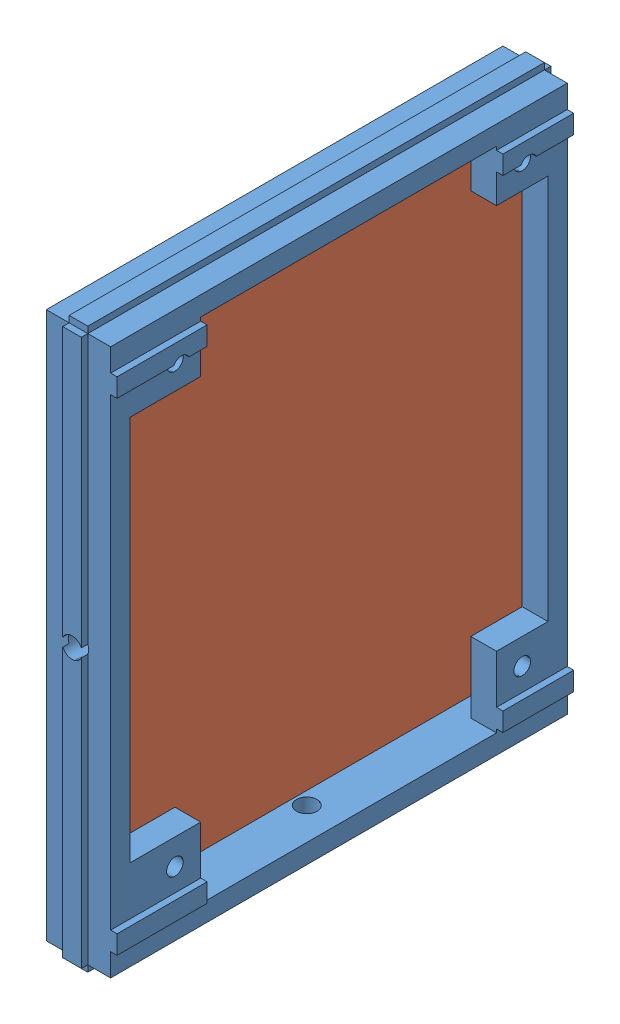
SolidWorks assembly Assem5, configuration Default. Lengths in mm.
Overall size (15.6 87 73).
11 component instances, 3 part files, 3 mates.
Components (placement in the parent):
- RLY08MakerBeamSupport-1: RLY08MakerBeamSupport [Default] at (8.7993 1.6144 41.7452) size (11 87 73)
- RLY08BoardAssembly-1: RLY08BoardAssembly [Default] at (44.7396 -28.8553 63.151) x (0 -1 0) z (-1 0 0) size (76 62 10.6)
  - RLY08Board-1: RLY08Board [Default] at (-74.4697 12.5942 29.9403) size (76 62 1.6)
  - Relay-ED2-5NU-1: Relay-ED2-5NU [Default] at (-96.9697 -8.9058 31.5403) size (14.8 7.35 9)
  - Relay-ED2-5NU-2: Relay-ED2-5NU [Default] at (-96.9697 2.5942 31.5403) size (14.8 7.35 9)
  - Relay-ED2-5NU-3: Relay-ED2-5NU [Default] at (-96.9697 14.0942 31.5403) size (14.8 7.35 9)
  - Relay-ED2-5NU-4: Relay-ED2-5NU [Default] at (-96.9697 25.5942 31.5403) size (14.8 7.35 9)
  - Relay-ED2-5NU-5: Relay-ED2-5NU [Default] at (-66.3697 -8.9058 31.5403) size (14.8 7.35 9)
  - Relay-ED2-5NU-6: Relay-ED2-5NU [Default] at (-66.3697 2.5942 31.5403) size (14.8 7.35 9)
  - Relay-ED2-5NU-7: Relay-ED2-5NU [Default] at (-66.3697 14.0942 31.5403) size (14.8 7.35 9)
  - Relay-ED2-5NU-8: Relay-ED2-5NU [Default] at (-66.3697 25.5942 31.5403) size (14.8 7.35 9)
Mates (geometry in assembly coordinates):
- Concentric1: concentric: cylinder of RLY08MakerBeamSupport-1 through (19.7993 79.6144 48.7452) axis (-1 0 0) radius 1.3; cylinder of RLY08BoardAssembly-1/RLY08Board-1 through (13.1993 79.6144 48.7452) axis (1 0 0) radius 1.6
- Coincident1: coincident: plane of RLY08MakerBeamSupport-1 through (14.7993 1.6144 41.7452) normal (-1 0 0); plane of RLY08BoardAssembly-1/RLY08Board-1 through (14.7993 99.4039 87.3894) normal (1 0 0)
- Concentric2: concentric anti-aligned: cylinder of RLY08MakerBeamSupport-1 through (19.7993 11.6144 48.7452) axis (-1 0 0) radius 1.3; cylinder of RLY08BoardAssembly-1/RLY08Board-1 through (13.1993 11.6144 48.7452) axis (1 0 0) radius 1.6
